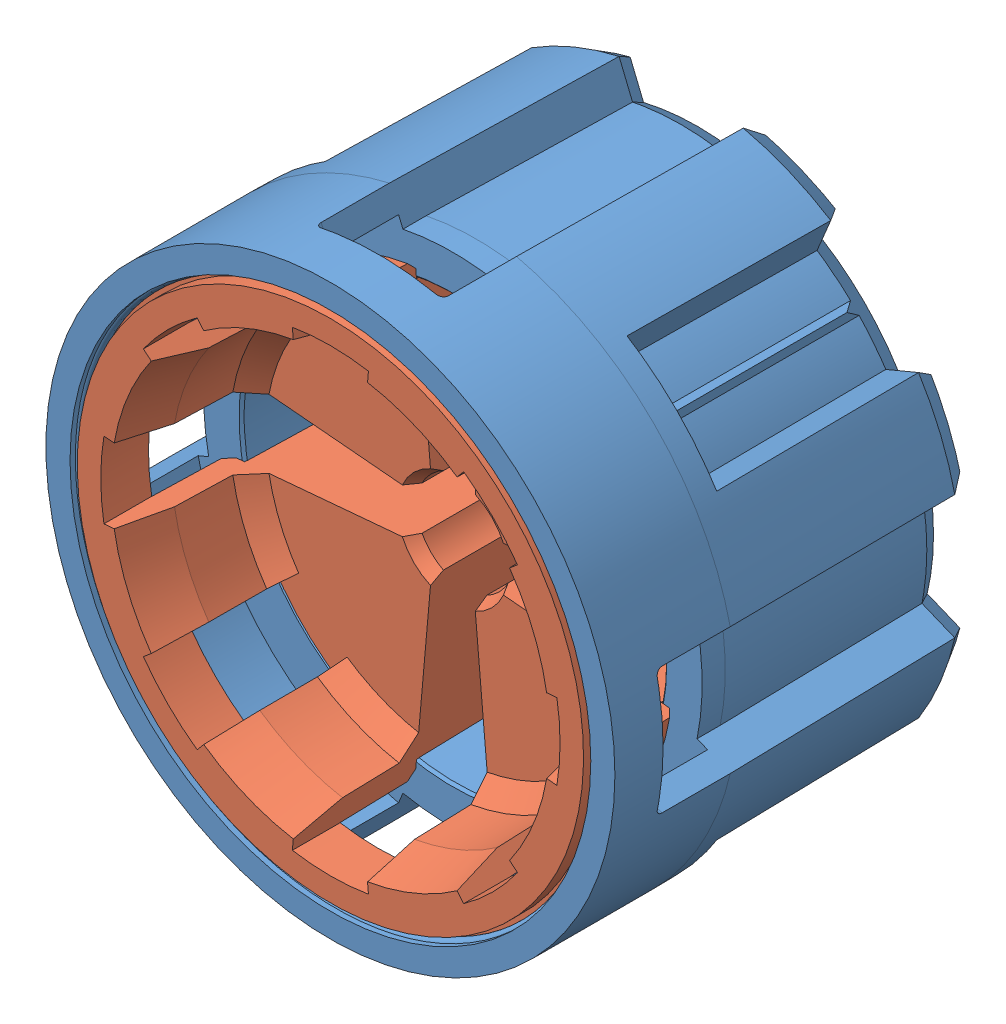
SolidWorks assembly Assem2, configuration Default. Lengths in mm.
Overall size (11.8 11.8 7.62).
2 component instances, 2 part files, 3 mates.
Components (placement in the parent):
- CENTER INSERT WITH 8 SPLINES-1: CENTER INSERT WITH 8 SPLINES [Default] at origin size (11.8 11.8 7.62)
- CENTER INSERT-1: CENTER INSERT [Default] at (0 0 -3.81) size (10.8 10.8 7.62)
Mates (geometry in assembly coordinates):
- Coincident1: coordinate: point of CENTER INSERT WITH 8 SPLINES-1; point of assembly
- Concentric1: concentric aligned: cone of CENTER INSERT WITH 8 SPLINES-1 through (0 0 -2.54) axis (0 0 -1); cone of CENTER INSERT-1 through (0 0 -7.62) axis (0 0 -1)
- Coincident2: coincident aligned: plane of CENTER INSERT WITH 8 SPLINES-1 through (0 0 -7.62) normal (0 0 -1); plane of CENTER INSERT-1 through (0 4.2276 -7.62) normal (0 0 -1)
